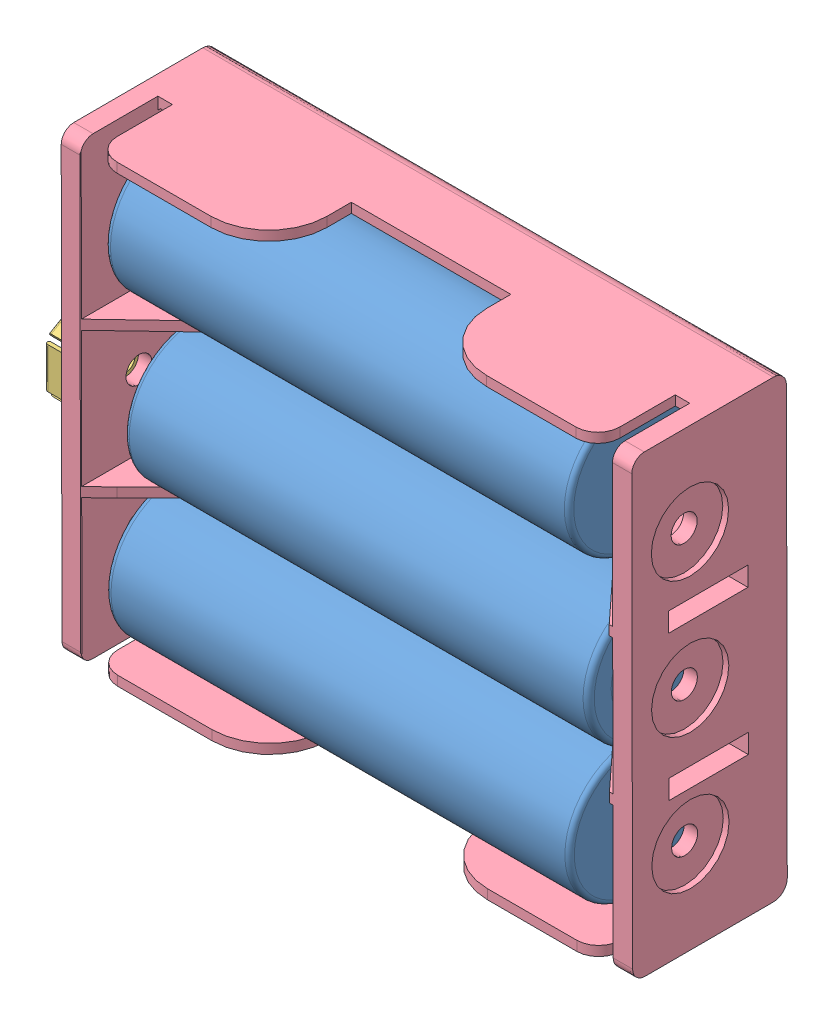
SolidWorks assembly 3AA ASSY pack, configuration Valor predeterminado. Lengths in mm.
Overall size (62.2 47.03 16.09).
6 component instances, 4 part files, 0 mates.
Components (placement in the parent):
- AA BATTERY-1: AA BATTERY [Valor predeterminado] at (32.71 79.0018 -164.738) x (0 -0.000009 -1) z (-1 0 0) size (14 14 49.5)
- AA BATTERY-2: AA BATTERY [Valor predeterminado] at (-13.29 94.0018 -164.7109) x (0 -0.000009 -1) z (1 0 0) size (14 14 49.5)
- AA BATTERY-3: AA BATTERY [Valor predeterminado] at (32.71 110.0018 -164.682) x (0 0.000009 1) z (-1 0 0) size (14 14 49.5)
- POS TERMINAL-1: POS TERMINAL [Valor predeterminado] at (-19.19 108.5 -163.6847) x (0 -0.001552 0.999999) z (-1 0 0) size (7 7 3.1)
- NEG TERMINAL-1: NEG TERMINAL [Valor predeterminado] at (-19.79 94.5 -163.71) x (0 0 1) z (-1 0 0) size (9 10.39 3.8)
- 3 aa battery-1: 3 aa battery [Valor predeterminado] at (64.21 76.0181 -173.7435) x (1 0 0) z (0 -0.001809 0.999998) size (59 47 16)
